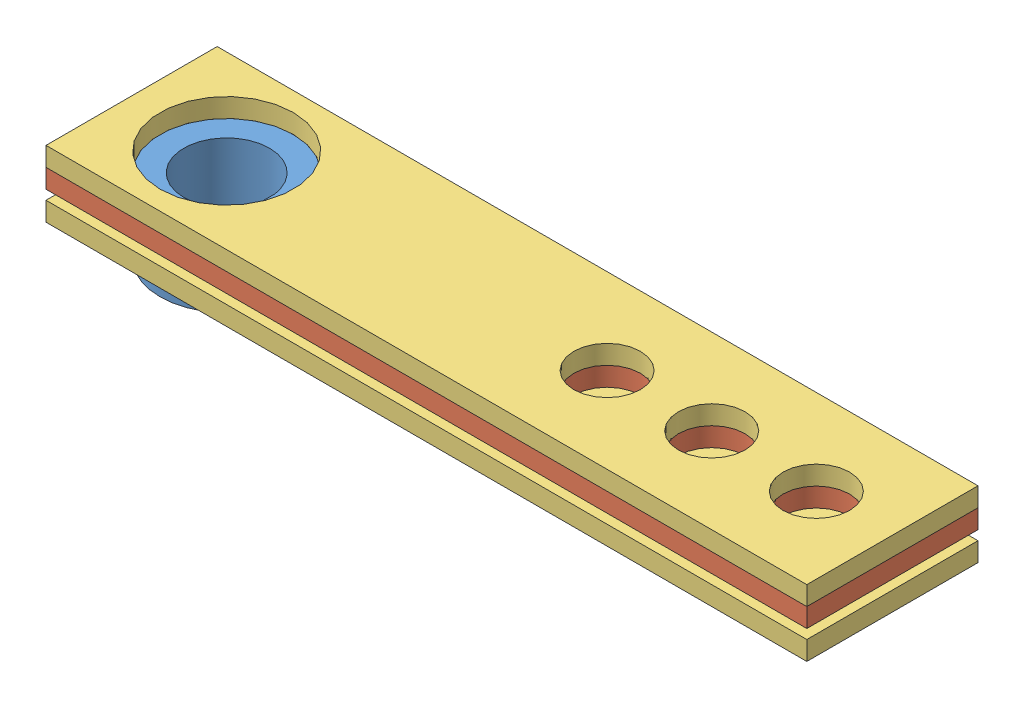
SolidWorks assembly 伺服馬達SG90用轉軸片壓克力固定組合[01-v1.0], configuration Default. Lengths in mm.
Overall size (40 4.9 9).
4 component instances, 3 part files, 9 mates.
Components (placement in the parent):
- 伺服馬達SG90用轉軸片[01-v1.0]-1: 伺服馬達SG90用轉軸片[01-v1.0] [Default] at (-1.3055 11.2909 16.7672) size (19.5 3.9 7)
- 伺服馬達SG90用轉軸片壓克力套[01-v1.0]-1: 伺服馬達SG90用轉軸片壓克力套[01-v1.0] [Default] at (13.6945 10.2909 16.7672) size (40 1 9)
- 伺服馬達SG90用轉軸片壓克力套[02-v1.0]-1: 伺服馬達SG90用轉軸片壓克力套[02-v1.0] [Default] at (13.6945 8.7909 16.7672) size (40 1 9)
- 伺服馬達SG90用轉軸片壓克力套[02-v1.0]-2: 伺服馬達SG90用轉軸片壓克力套[02-v1.0] [Default] at (13.6945 11.2909 16.7672) size (40 1 9)
Mates (geometry in assembly coordinates):
- Concentric1: concentric aligned: cylinder of 伺服馬達SG90用轉軸片[01-v1.0]-1 through (-1.3055 7.3909 16.7672) axis (0 1 0) radius 3.5; cylinder of 伺服馬達SG90用轉軸片壓克力套[01-v1.0]-1 through (-1.3055 8.2909 16.7672) axis (0 1 0) radius 3.5
- Coincident1: coincident aligned: plane of 伺服馬達SG90用轉軸片[01-v1.0]-1 through (-1.3055 11.2909 16.7672) normal (0 1 0); plane of 伺服馬達SG90用轉軸片壓克力套[01-v1.0]-1 through (8.2169 11.2909 28.3569) normal (0 1 0)
- Concentric2: concentric aligned: cylinder of 伺服馬達SG90用轉軸片[01-v1.0]-1 through (-1.3055 7.3909 16.7672) axis (0 1 0) radius 3.5; cylinder of 伺服馬達SG90用轉軸片壓克力套[02-v1.0]-1 through (-1.3055 6.7909 16.7672) axis (0 1 0) radius 3.5
- Coincident2: coincident anti-aligned: plane of 伺服馬達SG90用轉軸片[01-v1.0]-1 through (-1.3055 9.7909 16.7672) normal (0 -1 0); plane of 伺服馬達SG90用轉軸片壓克力套[02-v1.0]-1 through (8.2169 9.7909 28.3569) normal (0 1 0)
- Concentric3: concentric aligned: cylinder of 伺服馬達SG90用轉軸片[01-v1.0]-1 through (-1.3055 7.3909 16.7672) axis (0 1 0) radius 3.5; cylinder of 伺服馬達SG90用轉軸片壓克力套[02-v1.0]-2 through (-1.3055 9.2909 16.7672) axis (0 1 0) radius 3.5
- Coincident3: coincident anti-aligned: plane of 伺服馬達SG90用轉軸片[01-v1.0]-1 through (-1.3055 11.2909 16.7672) normal (0 1 0); plane of 伺服馬達SG90用轉軸片壓克力套[02-v1.0]-2 through (8.2169 11.2909 28.3569) normal (0 -1 0)
- Concentric4: concentric aligned: cylinder of 伺服馬達SG90用轉軸片壓克力套[01-v1.0]-1 through (14.8827 8.2909 36.4698) axis (0 1 0) radius 1.75; cylinder of 伺服馬達SG90用轉軸片壓克力套[02-v1.0]-2 through (14.8827 9.2909 36.4698) axis (0 1 0) radius 1.75
- Concentric5: concentric aligned: cylinder of 伺服馬達SG90用轉軸片壓克力套[01-v1.0]-1 through (14.8827 8.2909 36.4698) axis (0 1 0) radius 1.75; cylinder of 伺服馬達SG90用轉軸片壓克力套[02-v1.0]-1 through (14.8827 6.7909 36.4698) axis (0 1 0) radius 1.75
- Coincident4: coincident anti-aligned: plane of 伺服馬達SG90用轉軸片[01-v1.0]-1 through (-1.1377 9.7909 19.5896) normal (0.059354 0 0.998237); plane of 伺服馬達SG90用轉軸片壓克力套[01-v1.0]-1 through (13.8095 8.2909 18.7009) normal (-0.059354 0 -0.998237)
